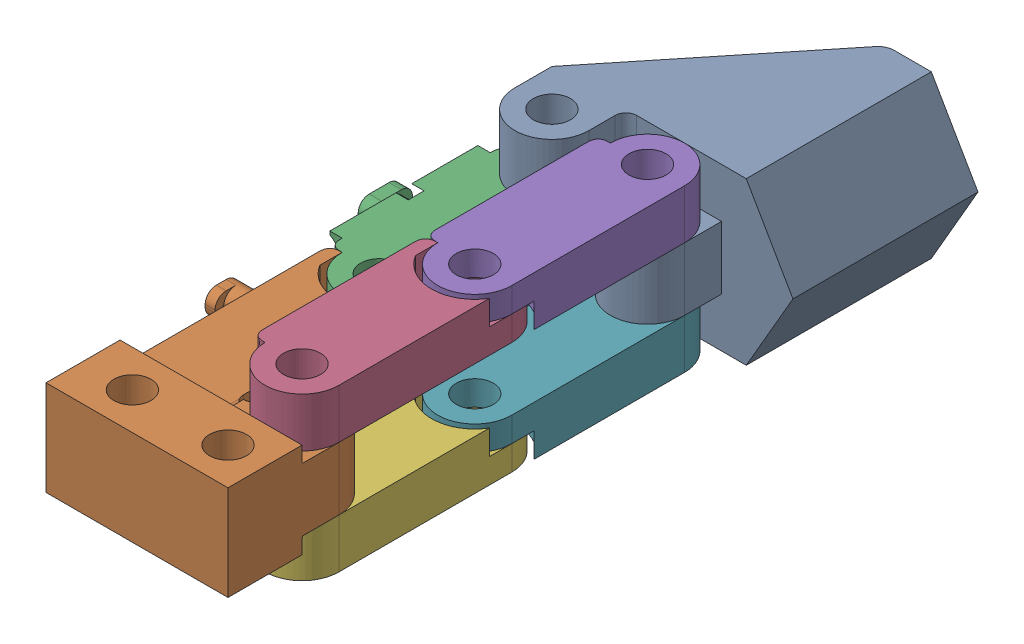
SolidWorks assembly finger_assembly, configuration Default. Lengths in mm.
Overall size (23.53 13.2 55).
7 component instances, 4 part files, 0 mates.
Components (placement in the parent):
- final_gripper-1: final_gripper [Default] at (8.3431 -3.9737 16.4837) size (23.53 13.1 21)
- support_gripper-1: support_gripper [Default] at (1.4681 -3.9737 50.4837) size (17.55 7.7 26)
- rod_gripper_external-1: rod_gripper_external [Default] at (-2.4069 -3.9737 26.4837) x (0 0 1) z (1 0 0) size (20 4.1 10)
- rod_gripper_internal-1: rod_gripper_internal [Default] at (5.3431 0.5763 40.4837) x (0 0 -1) z (1 0 0) size (20 4.1 7.05)
- rod_gripper_internal-4: rod_gripper_internal [Default] at (5.3431 0.5763 26.4837) x (0 0 1) z (1 0 0) size (20 4.1 7.05)
- rod_gripper_internal-5: rod_gripper_internal [Default] at (5.3431 -8.5237 40.4837) x (0 0 -1) z (1 0 0) size (20 4.1 7.05)
- rod_gripper_internal-6: rod_gripper_internal [Default] at (5.3431 -8.5237 26.4837) x (0 0 1) z (1 0 0) size (20 4.1 7.05)
